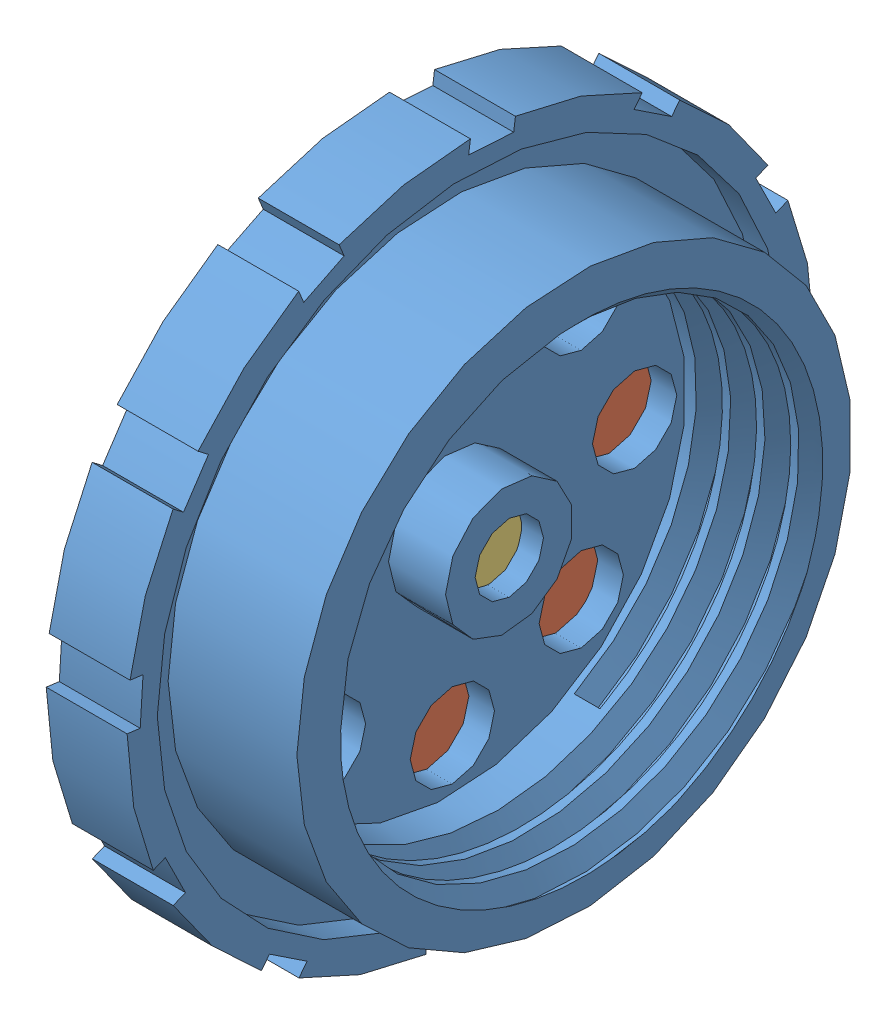
SolidWorks assembly Assy_Ambu-Bag_Inlet_Inner, configuration Default. Lengths in mm.
Overall size (17.91 60.3 60.3).
3 component instances, 3 part files, 4 mates.
Components (placement in the parent):
- Ambu-Bag_Inlet_Inner-1: Ambu-Bag_Inlet_Inner [Default] at origin size (17.56 60.3 60.3)
- Ambu-Bag_Inlet_Inner_Seal-1: Ambu-Bag_Inlet_Inner_Seal [Default] at (2.65 0 0) x (0 0 -1) z (1 0 0) size (51 51 0.6)
- Ambu-Bag_Inlet_Inner_Flange-1: Ambu-Bag_Inlet_Inner_Flange [Default] at (-0.35 0 0) size (9 26 26)
Mates (geometry in assembly coordinates):
- Coincident1: coincident: plane of assembly; plane of assembly; plane of Ambu-Bag_Inlet_Inner-1 through (3.25 0 0) normal (-1 0 0); plane of Ambu-Bag_Inlet_Inner_Seal-1 through (3.25 0 0) normal (1 0 0)
- Concentric1: concentric: cylinder of assembly; cylinder of assembly; cylinder of Ambu-Bag_Inlet_Inner-1 through (0 0 0) axis (1 0 0) radius 3; cylinder of Ambu-Bag_Inlet_Inner_Seal-1 through (3.25 0 0) axis (-1 0 0) radius 9.25
- Coincident2: coincident: plane of assembly; plane of assembly; plane of Ambu-Bag_Inlet_Inner-1 through (3.25 0 0) normal (-1 0 0); plane of Ambu-Bag_Inlet_Inner_Flange-1 through (3.25 9 0) normal (1 0 0)
- Concentric2: concentric: cylinder of assembly; cylinder of assembly; cylinder of Ambu-Bag_Inlet_Inner-1 through (0 0 0) axis (1 0 0) radius 3; cylinder of Ambu-Bag_Inlet_Inner_Flange-1 through (-0.35 0 0) axis (-1 0 0) radius 13
